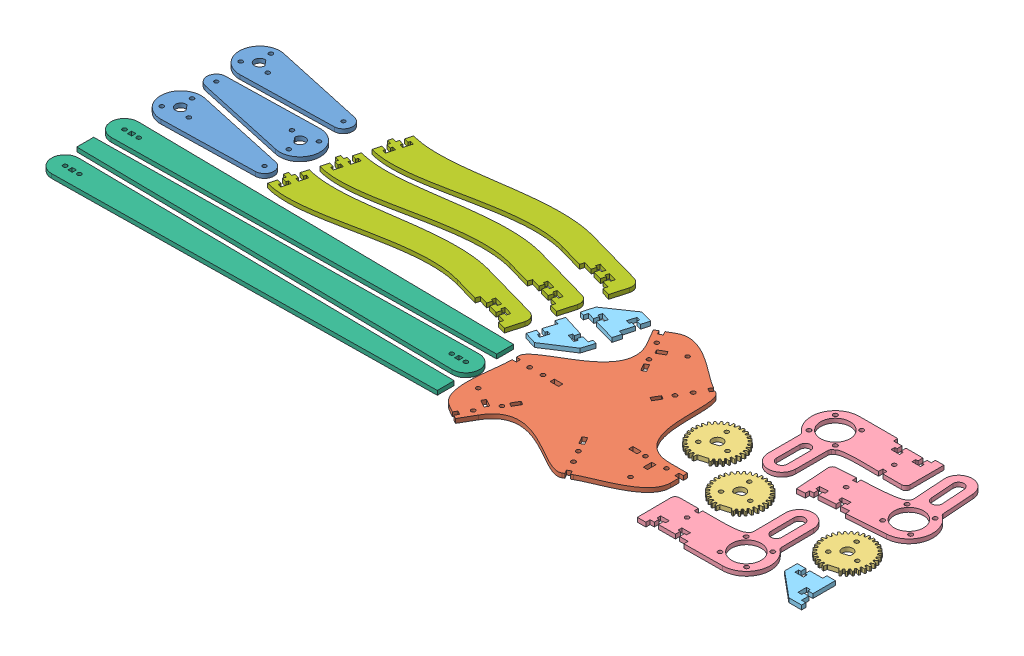
SolidWorks assembly cut_parts_18, configuration Default. Lengths in mm.
Overall size (609.6 3.17 304.8).
19 component instances, 7 part files, 27 mates.
Components (placement in the parent):
- arm_upper-1: arm_upper [Default] at (-365.7174 0 -27.4895) x (-0.995314 0 -0.096698) z (0 -1 0) size (92.08 30.48 3.17)
- arm_upper-2: arm_upper [Default] at (-300.1332 0 7.9317) x (0.995314 0 0.096698) z (0 -1 0) size (92.08 30.48 3.17)
- arm_upper-3: arm_upper [Default] at (-366.2336 0 31.1761) x (-0.995314 0 -0.096698) z (0 -1 0) size (92.08 30.48 3.17)
- baseplate-1: baseplate [Default] at (-14.4479 -3.175 69.2704) size (143.92 3.17 142.53)
- gear_stepper-1: gear_stepper [Default] at (172.621 0 69.6769) x (1 0 0) z (0 -1 0) size (37.03 37 3.17)
- gear_stepper-2: gear_stepper [Default] at (93.3739 0 70.9115) x (1 0 0) z (0 -1 0) size (37.03 37 3.17)
- gear_stepper-3: gear_stepper [Default] at (52.4693 0 47.0565) x (1 0 0) z (0 -1 0) size (37.03 37 3.17)
- motor_plate-1: motor_plate [Default] at (89.3227 0 -4.566) x (1 0 0) z (0 -1 0) size (81.5 68.48 3.17)
- motor_plate-2: motor_plate [Default] at (174.8794 0 25.7976) x (-0.997647 0 0.068558) z (0 -1 0) size (81.5 68.48 3.17)
- motor_plate-3: motor_plate [Default] at (134.9949 0 107.9043) x (-0.999969 0 0.007898) z (0 -1 0) size (81.5 68.48 3.17)
- motor_plate_support-1: motor_plate_support [Default] at (187.1351 0 110.1264) x (1 0 0) z (0 -1 0) size (28.57 28.57 3.17)
- motor_plate_support-2: motor_plate_support [Default] at (-69.0848 0 28.3739) x (0.296717 0 -0.954965) z (0 -1 0) size (28.57 28.57 3.17)
- motor_plate_support-3: motor_plate_support [Default] at (-71.0667 0 14.4741) x (-0.271232 0 0.962514) z (0 -1 0) size (28.57 28.57 3.17)
- support_lower-1: support_lower [Default] at (-371.7017 0 112.6423) x (0 -1 0) z (0 0 -1) size (3.17 295.91 20.32)
- support_lower-2: support_lower [Default] at (-93.8088 0 89.676) x (0 -1 0) z (0 0 1) size (3.17 295.91 20.32)
- support_lower-3: support_lower [Default] at (-373.0213 0 66.7274) x (0 -1 0) z (0 0 -1) size (3.17 295.91 20.32)
- support_upper-1: support_upper [Default] at (-132.8933 0 -21.5393) x (-0.962514 0 -0.271231) z (0 -1 0) size (180.97 63.5 3.17)
- support_upper-2: support_upper [Default] at (-150.1164 0 39.5804) x (-0.962514 0 -0.271231) z (0 -1 0) size (180.97 63.5 3.17)
- support_upper-3: support_upper [Default] at (-141.5049 0 9.0205) x (-0.962514 0 -0.271231) z (0 -1 0) size (180.97 63.5 3.17)
Mates (geometry in assembly coordinates):
- Distance7: distance = 6.35 mm: line of arm_upper-1 through (-296.0438 0 -13.7518) axis (-0.999767 0 0.021608); line of arm_upper-2 through (-369.8068 0 -5.8061) axis (0.999767 0 -0.021608)
- Distance6: distance = 6.35 mm: line of arm_upper-2 through (-303.3892 0 22.8198) axis (-0.976911 0 -0.213648); line of arm_upper-3 through (-362.9776 0 16.288) axis (0.976911 0 0.213648)
- Distance1: distance = 6.35 mm: point of support_upper-2; point of support_upper-3
- Distance3: distance = 6.35 mm: point of support_upper-3; point of support_upper-1
- Coincident25: coincident aligned: line of support_upper-2 through (-279.0383 0 28.8485) axis (0.271231 0 -0.962514); line of support_upper-3 through (-270.4268 0 -1.7113) axis (0.271231 0 -0.962514)
- Coincident26: coincident aligned: line of support_upper-1 through (-261.8152 0 -32.2712) axis (0.271231 0 -0.962514); line of support_upper-3 through (-270.4268 0 -1.7113) axis (0.271231 0 -0.962514)
- Distance8: distance = 6.35 mm: line of support_lower-3 through (-87.2713 0 73.0774) axis (-0.999911 0 0.013335); line of support_lower-2 through (-379.5588 0 83.326) axis (0.999911 0 -0.013335)
- Distance5: distance = 6.35 mm: line of support_lower-1 through (-371.5662 0 102.4832) axis (0.999911 0 0.013335); line of support_lower-2 through (-93.9443 0 99.8351) axis (-0.999911 0 -0.013335)
- Coincident45: coincident aligned: plane of baseplate-1 through (24.6831 -3.175 49.7697) normal (0 -1 0); plane of gear_stepper-3 through (53.0266 -3.175 65.4026) normal (0 -1 0)
- Coincident46: coincident aligned: plane of baseplate-1 through (24.6831 -3.175 49.7697) normal (0 -1 0); plane of motor_plate-1 through (115.3331 -3.175 5.9579) normal (0 -1 0)
- Coincident47: coincident aligned: plane of baseplate-1 through (24.6831 -3.175 49.7697) normal (0 -1 0); plane of motor_plate-2 through (148.2086 -3.175 17.0817) normal (0 -1 0)
- Coincident48: coincident aligned: plane of baseplate-1 through (24.6831 -3.175 49.7697) normal (0 -1 0); plane of gear_stepper-1 through (173.1782 -3.175 88.0231) normal (0 -1 0)
- Coincident49: coincident aligned: plane of baseplate-1 through (24.6831 -3.175 49.7697) normal (0 -1 0); plane of motor_plate_support-1 through (190.3101 -3.175 129.7479) normal (0 -1 0)
- Coincident50: coincident aligned: plane of baseplate-1 through (24.6831 -3.175 49.7697) normal (0 -1 0); plane of motor_plate-3 through (108.9021 -3.175 97.5861) normal (0 -1 0)
- Coincident51: coincident aligned: plane of baseplate-1 through (24.6831 -3.175 49.7697) normal (0 -1 0); plane of gear_stepper-2 through (93.9312 -3.175 89.2577) normal (0 -1 0)
- Coincident52: coincident aligned: plane of baseplate-1 through (24.6831 -3.175 49.7697) normal (0 -1 0); plane of support_upper-2 through (-219.9081 -3.175 43.0041) normal (0 -1 0)
- Coincident53: coincident aligned: plane of baseplate-1 through (24.6831 -3.175 49.7697) normal (0 -1 0); plane of support_upper-3 through (-211.2965 -3.175 12.4442) normal (0 -1 0)
- Coincident54: coincident aligned: plane of baseplate-1 through (24.6831 -3.175 49.7697) normal (0 -1 0); plane of support_upper-1 through (-202.685 -3.175 -18.1156) normal (0 -1 0)
- Coincident55: coincident aligned: plane of baseplate-1 through (24.6831 -3.175 49.7697) normal (0 -1 0); plane of motor_plate_support-3 through (-90.8138 -3.175 12.2081) normal (0 -1 0)
- Coincident56: coincident aligned: plane of baseplate-1 through (24.6831 -3.175 49.7697) normal (0 -1 0); plane of motor_plate_support-2 through (-49.4048 -3.175 31.1639) normal (0 -1 0)
- Coincident57: coincident aligned: plane of baseplate-1 through (24.6831 -3.175 49.7697) normal (0 -1 0); plane of support_lower-3 through (-373.0213 -3.175 66.7274) normal (0 -1 0)
- Coincident58: coincident aligned: plane of baseplate-1 through (24.6831 -3.175 49.7697) normal (0 -1 0); plane of support_lower-2 through (-93.8088 -3.175 89.676) normal (0 -1 0)
- Coincident59: coincident aligned: plane of baseplate-1 through (24.6831 -3.175 49.7697) normal (0 -1 0); plane of support_lower-1 through (-371.7017 -3.175 112.6423) normal (0 -1 0)
- Coincident60: coincident aligned: plane of baseplate-1 through (24.6831 -3.175 49.7697) normal (0 -1 0); plane of arm_upper-1 through (-296.1948 -3.175 -20.7351) normal (0 -1 0)
- Coincident61: coincident aligned: plane of baseplate-1 through (24.6831 -3.175 49.7697) normal (0 -1 0); plane of arm_upper-2 through (-369.6559 -3.175 1.1773) normal (0 -1 0)
- Coincident62: coincident aligned: plane of baseplate-1 through (24.6831 -3.175 49.7697) normal (0 -1 0); plane of arm_upper-3 through (-296.7109 -3.175 37.9305) normal (0 -1 0)
- Coincident63: coincident aligned: plane of baseplate-1 through (24.6831 0 49.7697) normal (0 1 0); plane of assembly through (0 0 0) normal (0 1 0)
